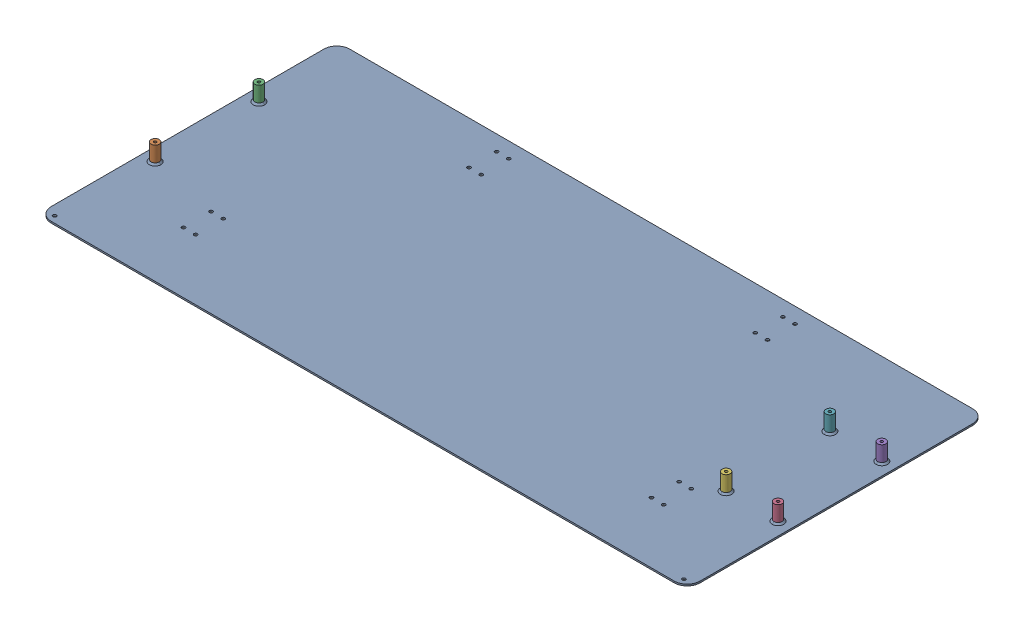
SolidWorks assembly GE-16039_ASM, configuration Default. Lengths in mm.
Overall size (1270 36.51 584.2).
8 component instances, 3 part files, 0 mates.
Components (placement in the parent):
- GE-16039_ASM-1: GE-16039_ASM [Default] at origin size (1241.62 3.21 225.78)
- GE-16016-1: GE-16016 [Default] at origin size (1270 3.17 584.2)
- GE-16039-01-1: GE-16039-01 [Default] at (-609.6 3.175 88.9) size (15.88 33.34 15.88)
- GE-16039-01-2: GE-16039-01 [Default] at (-609.6 3.175 -114.3) size (15.88 33.34 15.88)
- GE-16039-01-3: GE-16039-01 [Default] at (609.6 3.175 88.9) x (0 0 -1) z (1 0 0) size (15.88 33.34 15.88)
- GE-16039-01-4: GE-16039-01 [Default] at (609.6 3.175 -114.3) x (0 0 -1) z (1 0 0) size (15.88 33.34 15.88)
- GE-16039-01-5: GE-16039-01 [Default] at (508 3.175 88.9) x (0 0 -1) z (1 0 0) size (15.88 33.34 15.88)
- GE-16039-01-6: GE-16039-01 [Default] at (508 3.175 -114.3) x (0 0 -1) z (1 0 0) size (15.88 33.34 15.88)
